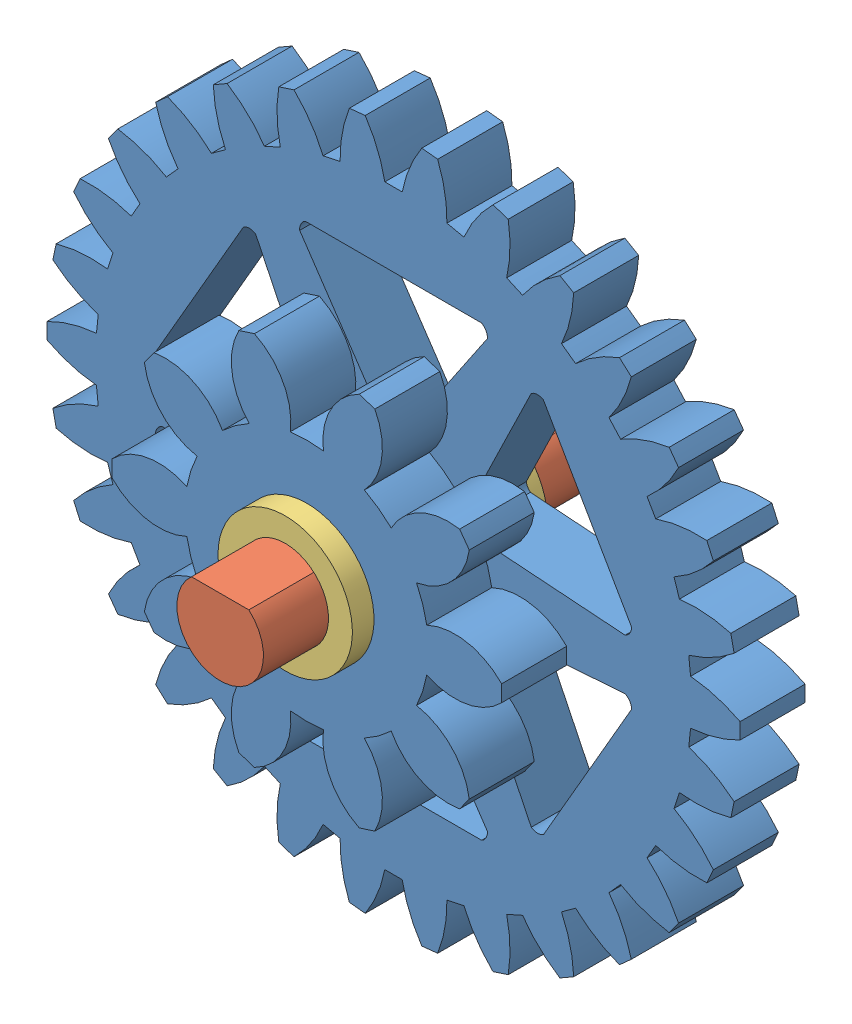
SolidWorks assembly secondShaft, configuration Default. Lengths in mm.
Overall size (32 31.89 15).
6 component instances, 3 part files, 12 mates.
Components (placement in the parent):
- root_gear-1: root_gear [30T 1.0Mod] at (-4.2891 9.5907 28.4653) size (32 31.89 3)
- root_gear-2: root_gear [10T 1.5Mod] at (-4.2891 9.5907 32.4653) size (18 17.34 3)
- axle-1: axle [15mm tall] at (-4.2891 9.5907 39.4653) size (4 3.5 15)
- spacer-1: spacer [1mm tall] at (-4.2891 9.5907 35.4653) size (6.2 6.2 1)
- spacer-2: spacer [1mm tall] at (-4.2891 9.5907 27.4653) size (6.2 6.2 1)
- spacer-3: spacer [1mm tall] at (-4.2891 9.5907 31.4653) size (6.2 6.2 1)
Mates (geometry in assembly coordinates):
- Concentric1: concentric aligned: cylinder of root_gear-2 through (-4.2891 9.5907 32.4653) axis (0 0 1) radius 2; cylinder of axle-1 through (-4.2891 9.5907 24.4653) axis (0 0 1) radius 2
- Coincident1: coincident anti-aligned: plane of root_gear-1 through (-5.612 11.0907 28.4653) normal (0 -1 0); plane of axle-1 through (-2.9662 11.0907 24.4653) normal (0 1 0)
- Concentric2: concentric aligned: cylinder of root_gear-1 through (-4.2891 9.5907 28.4653) axis (0 0 1) radius 2; cylinder of axle-1 through (-4.2891 9.5907 24.4653) axis (0 0 1) radius 2
- Concentric3: concentric anti-aligned: cylinder of axle-1 through (-4.2891 9.5907 24.4653) axis (0 0 1) radius 2; cylinder of spacer-1 through (-4.2891 9.5907 36.4653) axis (0 0 -1) radius 2
- Coincident2: coincident anti-aligned: plane of root_gear-2 through (-5.612 11.0907 32.4653) normal (0 -1 0); plane of axle-1 through (-2.9662 11.0907 24.4653) normal (0 1 0)
- Coincident3: coincident anti-aligned: plane of root_gear-2 through (-4.2891 9.5907 35.4653) normal (0 0 1); plane of spacer-1 through (-4.2891 9.5907 35.4653) normal (0 0 -1)
- Concentric4: concentric anti-aligned: cylinder of axle-1 through (-4.2891 9.5907 24.4653) axis (0 0 1) radius 2; cylinder of spacer-3 through (-4.2891 9.5907 32.4653) axis (0 0 -1) radius 2
- Coincident5: coincident anti-aligned: plane of root_gear-2 through (-4.2891 9.5907 32.4653) normal (0 0 -1); plane of spacer-3 through (-4.2891 9.5907 32.4653) normal (0 0 1)
- Coincident6: coincident anti-aligned: plane of root_gear-1 through (-4.2891 9.5907 31.4653) normal (0 0 1); plane of spacer-3 through (-4.2891 9.5907 31.4653) normal (0 0 -1)
- Distance2: distance = 3 mm aligned: plane of spacer-1 through (-4.2891 9.5907 36.4653) normal (0 0 1); plane of axle-1 through (-4.2891 9.5907 39.4653) normal (0 0 1)
- Concentric5: concentric anti-aligned: cylinder of axle-1 through (-4.2891 9.5907 24.4653) axis (0 0 1) radius 2; cylinder of spacer-2 through (-4.2891 9.5907 28.4653) axis (0 0 -1) radius 2
- Coincident8: coincident anti-aligned: plane of root_gear-1 through (-4.2891 9.5907 28.4653) normal (0 0 -1); plane of spacer-2 through (-4.2891 9.5907 28.4653) normal (0 0 1)
